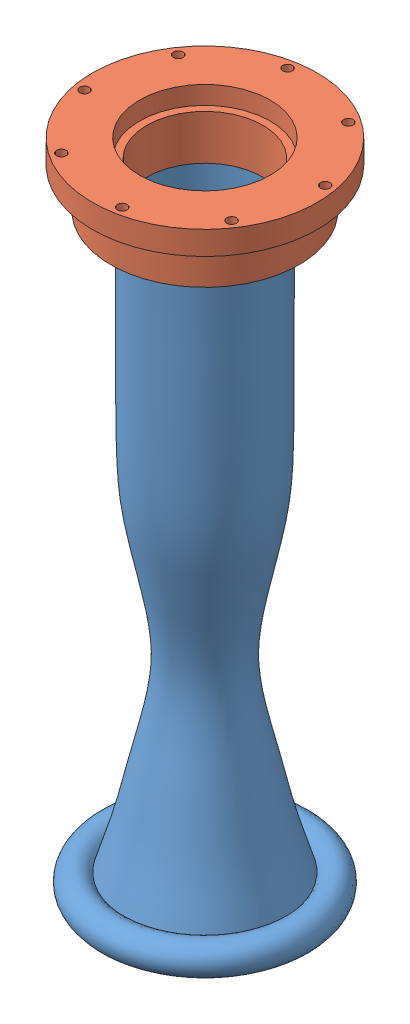
SolidWorks assembly LR101 Engine Assem, configuration Default. Lengths in mm.
Overall size (155.46 391.39 155.46).
3 component instances, 2 part files, 2 mates.
Components (placement in the parent):
- LR101 Engine-1: LR101 Engine [Default] at origin size (127.25 353.92 127.25)
  - Engine ID Profile (2) (1)-1: Engine ID Profile (2) (1) [Default] x (-1 0 0) z (0 0 1) size (127.25 353.92 127.25)
- LR101 Bottom Injector Plate-1: LR101 Bottom Injector Plate [Default] x (0.18264 0 0.98318) z (-0.98318 0 0.18264) size (133.35 37.46 133.35)
Mates (geometry in assembly coordinates):
- Concentric1: concentric aligned: circle of LR101 Engine-1/Engine ID Profile (2) (1)-1; circle of LR101 Bottom Injector Plate-1
- Coincident1: coincident anti-aligned: plane of LR101 Engine-1/Engine ID Profile (2) (1)-1 through (-76.2 0 50.8) normal (0 1 0); plane of LR101 Bottom Injector Plate-1 through (0 0 0) normal (0 -1 0)
